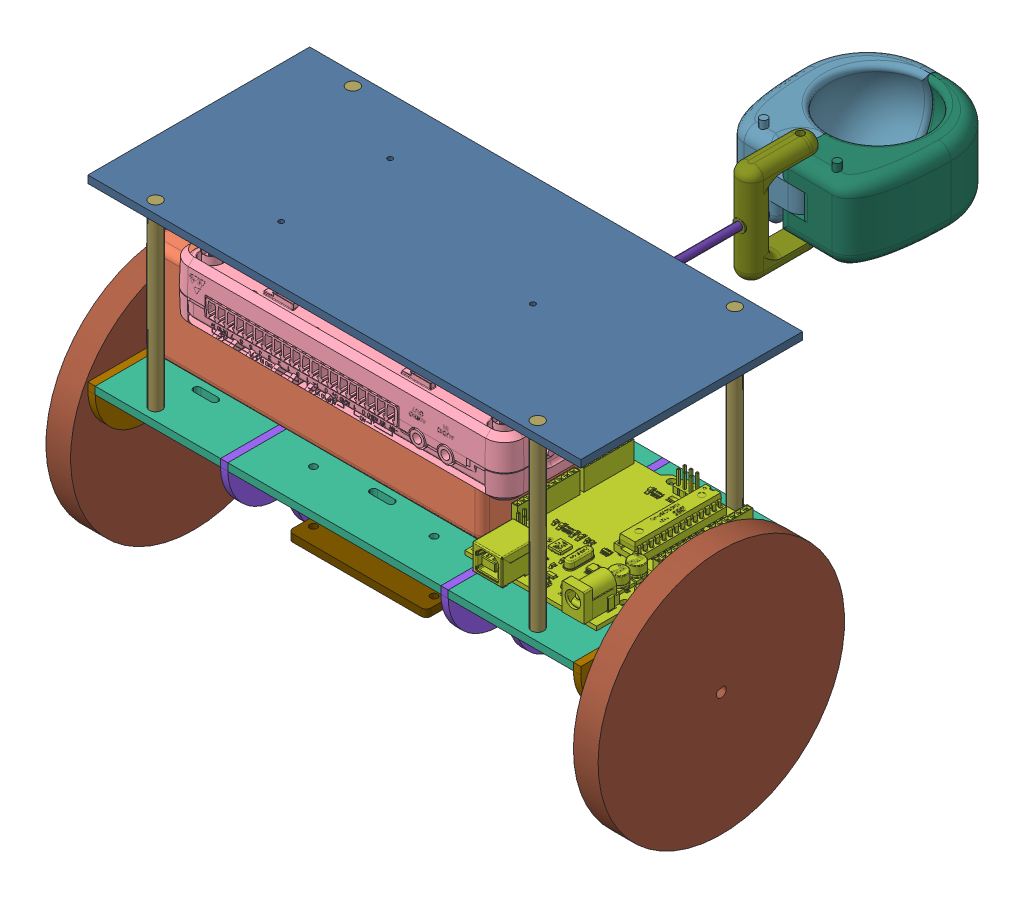
SolidWorks assembly Robot assembly, configuration Default. Lengths in mm.
Overall size (224 158.21 257.62).
26 component instances, 18 part files, 57 mates.
Components (placement in the parent):
- Motor-1: Motor [Default] at (-108.5 0 0) size (73 25 25)
- Motor-2: Motor [Default] at (108.5 0 0) x (-1 0 0) z (0 0 1) size (73 25 25)
- Battery-1: Battery [Default] at (38 45.5 0) x (0 0 1) z (0 -1 0) size (46 138 40)
- Motor controller PCB-1: Motor controller PCB [Default] at (0 16.5 0) x (-1 0 0) z (0 0 -1) size (56.02 3 71.58)
- myRIO-1: myRIO [Default] at (0 74.5241 0) x (0 0 1) z (0 -1 0) size (96.27 143.57 29.32)
- Orientation sensor-1: Orientation sensor [Default] at (0 -1.5 7.16) size (26.67 3 20.32)
- motor base layer-1: motor base layer [Default] at (0 22.5 0) size (200 3 90)
- arduino uno-1: arduino uno [Default] at (95.67 32.15 34.29) size (53.34 15.25 74.93)
- Rear motor bracket-3: Rear motor bracket [Default] at (46.2 0 0) x (0 0 1) z (-1 0 0) size (90 43 3)
- Rear motor bracket-4: Rear motor bracket [Default] at (-46.2 0 0) x (0 0 -1) z (1 0 0) size (90 43 3)
- motor bracket-3: motor bracket [Default] at (97 0 0) x (0 0 -1) z (1 0 0) size (90 38 3)
- motor bracket-4: motor bracket [Default] at (-97 0 0) x (0 0 1) z (-1 0 0) size (90 38 3)
- Arm base layer-1: Arm base layer [Default] at (0 95.2 0) size (200 3 90)
- wheel-1: wheel [Default] at (102 0 0) x (0 0.226028 -0.974121) z (1 0 0) size (100 100 10)
- wheel-2: wheel [Default] at (-102 0 0) x (0 0.027952 0.999609) z (-1 0 0) size (100 100 10)
- threaded rod-1: threaded rod [Default] at (77.5 22.5 40) size (5 75.7 5)
- threaded rod-2: threaded rod [Default] at (-77.5 22.5 40) x (-0.004998 0 -0.999988) z (0.999988 0 -0.004998) size (5 75.7 5)
- threaded rod-3: threaded rod [Default] at (-77.5 22.5 -40) size (5 75.7 5)
- threaded rod-4: threaded rod [Default] at (77.5 22.5 -40) size (5 75.7 5)
- Assem2-1: Assem2 [Default] at (3.659 51.9532 -140.4745) size (62.43 40 147.14)
  - dowel-1: dowel [Default] at origin size (3 30 3)
  - left gripper-1: left gripper [Default] at (-14.8819 0 -26.0678) x (0.99999 0 0.004537) z (-0.004537 0 0.99999) size (35.81 33.31 62.81)
  - right gripper-1: right gripper [Default] at (15.2281 0 -25.8671) x (-0.999961 0 -0.008794) z (-0.008794 0 0.999961) size (36.1 33.37 63.1)
  - Claw wrist-1: Claw wrist [Default] at (0 15 20) x (1 0 0) z (0 1 0) size (10 30 40)
  - silver steel arm-1: silver steel arm [Default] at (2.2998 0.9802 15) x (-0.392068 0.919936 0) z (0 0 1) size (3 3 75)
- orinetation sensor holder-1: orinetation sensor holder [Default] at (0 1.5 7.16) x (1 0 0) z (0 1 0) size (56.02 71.58 3)
Mates (geometry in assembly coordinates):
- Coincident1: coincident aligned: plane of Motor-1 through (-108.5 0 0) normal (0 0 1); plane of assembly through (0 0 0) normal (0 0 1)
- Coincident2: coincident aligned: plane of Motor-2 through (108.5 0 0) normal (0 0 1); plane of assembly through (0 0 0) normal (0 0 1)
- Concentric2: concentric anti-aligned: cylinder of Motor-1 through (-108.5 0 0) axis (-1 0 0) radius 2; cylinder of Motor-2 through (108.5 0 0) axis (1 0 0) radius 2
- Coincident3: coincident anti-aligned: plane of Motor-2 through (108.5 0 0) normal (0 -1 0); plane of assembly through (0 0 0) normal (0 1 0)
- Coincident4: coincident aligned: plane of motor base layer-1 through (0 22.5 0) normal (0 0 1); plane of assembly through (0 0 0) normal (0 0 1)
- Coincident5: coincident aligned: plane of motor base layer-1 through (0 22.5 0) normal (1 0 0); plane of assembly through (0 0 0) normal (1 0 0)
- Coincident7: coincident anti-aligned: plane of Motor controller PCB-1 through (0 16.5 0) normal (-1 0 0); plane of assembly through (0 0 0) normal (1 0 0)
- Coincident8: coincident anti-aligned: plane of Motor controller PCB-1 through (0 16.5 0) normal (0 0 -1); plane of assembly through (0 0 0) normal (0 0 1)
- Coincident9: coincident anti-aligned: plane of Battery-1 through (-100 25.5 -23) normal (0 -1 0); plane of motor base layer-1 through (0 25.5 0) normal (0 1 0)
- Parallel1: parallel aligned: plane of Battery-1 through (-100 25.5 23) normal (0 0 1); plane of motor base layer-1 through (-100 25.5 45) normal (0 0 1)
- Coincident12: coincident: plane of Battery-1 through (-100 45.5 0) normal (-1 0 0); line of motor base layer-1 through (-100 25.5 -15) axis (0 0 1)
- Coincident13: coincident aligned: plane of Battery-1 through (38 45.5 0) normal (0 0 1); plane of assembly through (0 0 0) normal (0 0 1)
- Distance3: distance = 5 mm anti-aligned: plane of motor base layer-1 through (0 25.5 0) normal (0 1 0); plane of arduino uno-1 through (95.67 30.5 34.29) normal (0 -1 0)
- Distance4: distance = 31 mm aligned: plane of arduino uno-1 through (69 32.15 34.29) normal (1 0 0); plane of motor base layer-1 through (100 25.5 45) normal (1 0 0)
- Distance5: distance = 3 mm anti-aligned: plane of Motor controller PCB-1 through (0 19.5 0) normal (0 1 0); plane of motor base layer-1 through (0 22.5 0) normal (0 -1 0)
- Coincident21: coincident: moEndPointRef_w of motor base layer-1; plane of arduino uno-1 through (95.67 32.15 0) normal (0 0 1)
- Coincident33: coincident anti-aligned: plane of motor base layer-1 through (97 22.5 -45) normal (1 0 0); plane of motor bracket-3 through (97 22.5 25) normal (-1 0 0)
- Coincident34: coincident aligned: plane of motor base layer-1 through (0 25.5 0) normal (0 1 0); plane of motor bracket-3 through (100 25.5 -45) normal (0 1 0)
- Coincident35: coincident anti-aligned: plane of motor base layer-1 through (100 22.5 15) normal (0 0 1); plane of motor bracket-3 through (100 22.5 15) normal (0 0 -1)
- Coincident36: coincident anti-aligned: plane of motor base layer-1 through (46.2 22.5 -15) normal (0 0 -1); plane of Rear motor bracket-3 through (43.2 22.5 -15) normal (0 0 1)
- Coincident37: coincident anti-aligned: plane of motor base layer-1 through (46.2 22.5 -45) normal (-1 0 0); plane of Rear motor bracket-3 through (46.2 22.5 -25) normal (1 0 0)
- Coincident38: coincident aligned: plane of motor base layer-1 through (0 25.5 0) normal (0 1 0); plane of Rear motor bracket-3 through (43.2 25.5 -45) normal (0 1 0)
- Concentric4: concentric aligned: cylinder of Motor-2 through (108.5 0 0) axis (1 0 0) radius 12.5; cylinder of Rear motor bracket-3 through (43.2 0 0) axis (1 0 0) radius 12.5
- Coincident39: coincident aligned: plane of motor base layer-1 through (0 25.5 0) normal (0 1 0); plane of Rear motor bracket-4 through (-43.2 25.5 45) normal (0 1 0)
- Coincident40: coincident anti-aligned: plane of motor base layer-1 through (-46.2 22.5 -15) normal (0 0 -1); plane of Rear motor bracket-4 through (-43.2 22.5 -15) normal (0 0 1)
- Coincident41: coincident anti-aligned: plane of motor base layer-1 through (-43.2 22.5 -45) normal (-1 0 0); plane of Rear motor bracket-4 through (-43.2 22.5 25) normal (1 0 0)
- Coincident42: coincident anti-aligned: plane of motor base layer-1 through (-97 22.5 45) normal (-1 0 0); plane of motor bracket-4 through (-97 22.5 -25) normal (1 0 0)
- Coincident43: coincident anti-aligned: plane of motor base layer-1 through (0 22.5 0) normal (0 -1 0); plane of motor bracket-4 through (-100 22.5 -15) normal (0 1 0)
- Coincident44: coincident anti-aligned: plane of motor base layer-1 through (-100 22.5 -15) normal (0 0 -1); plane of motor bracket-4 through (-100 22.5 -15) normal (0 0 1)
- Coincident45: coincident anti-aligned: plane of Motor-2 through (97 -3.5 0) normal (1 0 0); plane of motor bracket-3 through (97 22.5 25) normal (-1 0 0)
- Coincident46: coincident anti-aligned: plane of Motor-1 through (-97 3.5 0) normal (-1 0 0); plane of motor bracket-4 through (-97 22.5 -25) normal (1 0 0)
- Concentric5: concentric aligned: cylinder of motor base layer-1 through (77.5 22.5 40) axis (0 1 0) radius 2.5; cylinder of Arm base layer-1 through (77.5 95.2 40) axis (0 1 0) radius 2.5
- Concentric6: concentric aligned: cylinder of motor base layer-1 through (-77.5 22.5 40) axis (0 1 0) radius 2.5; cylinder of Arm base layer-1 through (-77.5 95.2 40) axis (0 1 0) radius 2.5
- Concentric7: concentric anti-aligned: cylinder of Motor-2 through (108.5 0 0) axis (1 0 0) radius 2; cylinder of wheel-1 through (112 0 0) axis (-1 0 0) radius 2
- Concentric8: concentric anti-aligned: cylinder of Motor-1 through (-108.5 0 0) axis (-1 0 0) radius 2; cylinder of wheel-2 through (-112 0 0) axis (1 0 0) radius 2
- Distance8: distance = 2 mm anti-aligned: plane of motor bracket-4 through (-100 22.5 -25) normal (-1 0 0); plane of wheel-2 through (-102 0 0) normal (1 0 0)
- Distance9: distance = 2 mm anti-aligned: plane of motor bracket-3 through (100 22.5 25) normal (1 0 0); plane of wheel-1 through (102 0 0) normal (-1 0 0)
- Concentric10: concentric anti-aligned: cylinder of motor base layer-1 through (77.5 22.5 40) axis (0 1 0) radius 2.5; cylinder of threaded rod-1 through (77.5 98.2 40) axis (0 -1 0) radius 2.5
- Coincident52: coincident aligned: plane of motor base layer-1 through (0 22.5 0) normal (0 -1 0); plane of threaded rod-1 through (77.5 22.5 40) normal (0 -1 0)
- Concentric11: concentric anti-aligned: cylinder of Arm base layer-1 through (-77.5 95.2 40) axis (0 1 0) radius 2.5; cylinder of threaded rod-2 through (-77.5 98.2 40) axis (0 -1 0) radius 2.5
- Concentric12: concentric anti-aligned: cylinder of Arm base layer-1 through (77.5 95.2 -40) axis (0 1 0) radius 2.5; cylinder of threaded rod-4 through (77.5 98.2 -40) axis (0 -1 0) radius 2.5
- Concentric13: concentric anti-aligned: cylinder of Arm base layer-1 through (-77.5 95.2 -40) axis (0 1 0) radius 2.5; cylinder of threaded rod-3 through (-77.5 98.2 -40) axis (0 -1 0) radius 2.5
- Coincident53: coincident aligned: plane of Arm base layer-1 through (0 98.2 0) normal (0 1 0); plane of threaded rod-2 through (-77.5 98.2 40) normal (0 1 0)
- Coincident54: coincident aligned: plane of Arm base layer-1 through (0 98.2 0) normal (0 1 0); plane of threaded rod-3 through (-77.5 98.2 -40) normal (0 1 0)
- Coincident55: coincident aligned: plane of Arm base layer-1 through (0 98.2 0) normal (0 1 0); plane of threaded rod-4 through (77.5 98.2 -40) normal (0 1 0)
- Coincident56: coincident aligned: plane of myRIO-1 through (0 74.5241 0) normal (0 0 1); plane of assembly through (0 0 0) normal (0 0 1)
- Distance10: distance = 2 mm anti-aligned: plane of myRIO-1 through (0 63.5 0) normal (0 -1 0); plane of Battery-1 through (-100 65.5 -23) normal (0 1 0)
- Coincident59: coincident anti-aligned: plane of myRIO-1 through (0 74.5241 0) normal (-1 0 0); plane of assembly through (0 0 0) normal (1 0 0)
- Coincident61: coincident: moEndPointRef_w of Orientation sensor-1; line of assembly
- Parallel2: parallel aligned: plane of Orientation sensor-1 through (0 1.5 7.16) normal (0 1 0); plane of motor base layer-1 through (0 25.5 0) normal (0 1 0)
- Parallel3: parallel aligned: plane of Orientation sensor-1 through (-13.335 1.5 17.32) normal (0 0 1); plane of motor base layer-1 through (-100 25.5 45) normal (0 0 1)
- Coincident66: coincident aligned: plane of Orientation sensor-1 through (0 -1.5 7.16) normal (1 0 0); plane of assembly through (0 0 0) normal (1 0 0)
- InPlace1: in place: plane of Orientation sensor-1 through (0 1.5 7.16) normal (0 1 0); plane of ? through (0 1.5 0) normal (0 1 0); moOrthogonalPlaneRef_w of Orientation sensor-1 through (0 1.5 7.16) normal (0 1 0); plane of ? through (0 1.5 0) normal (0 0 -1); plane of Orientation sensor-1 through (0 1.5 7.16) normal (0 1 0); plane of ? through (0 1.5 0) normal (1 0 0); plane of Orientation sensor-1 through (0 1.5 7.16) normal (0 1 0); unknown of orinetation sensor holder-1
- Coincident67: coincident aligned: plane of Orientation sensor-1; plane of orinetation sensor holder-1
- Coincident68: coincident aligned: moOrthogonalPlaneRef_w of Orientation sensor-1 through (0 1.5 7.16) normal (0 0 -1); plane of orinetation sensor holder-1 through (0 1.5 7.16) normal (0 0 -1)
- Coincident69: coincident anti-aligned: moOrthogonalPlaneRef_w of Orientation sensor-1 through (0 1.5 7.16) normal (-1 0 0); plane of orinetation sensor holder-1 through (0 1.5 7.16) normal (1 0 0)
- Coincident70: coincident aligned: plane of motor base layer-1 through (0 22.5 0) normal (0 -1 0); plane of threaded rod-2 through (-77.5 22.5 40) normal (0 -1 0)
